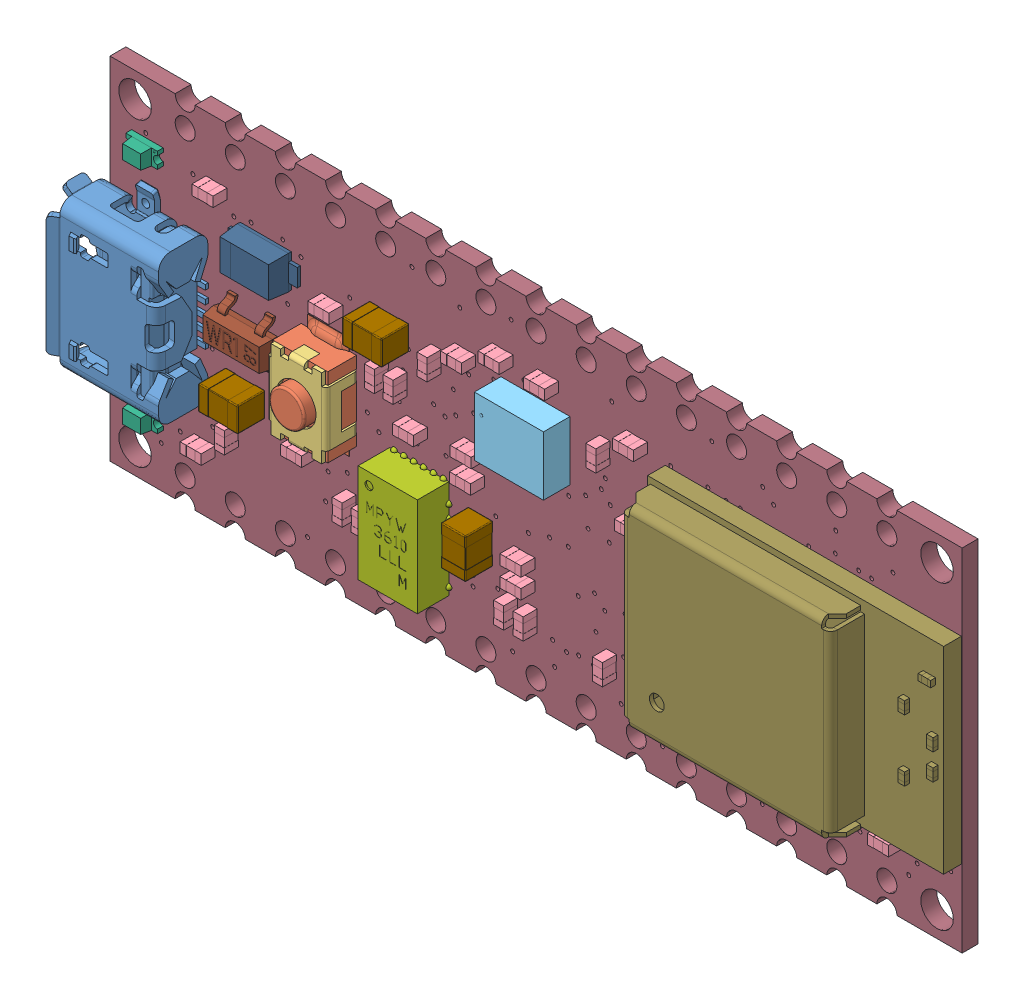
SolidWorks assembly Nano33BLE, configuration Default. Lengths in mm.
Overall size (43.8 17.78 3.58).
49 component instances, 13 part files, 0 mates.
Components (placement in the parent):
- Nano33BLE.step-1: Nano33BLE.step [Default] at origin size (43.8 17.78 3.58)
  - NANO33BLE_V2.0 v1.step-1: NANO33BLE_V2.0 v1.step [Default] at origin size (43.8 17.78 3.58)
    - 3DComponents.step-1: 3DComponents.step [Default] at origin size (43.76 12.41 2.95)
      - zx62-ab-5pa_31_ v1.step-1: zx62-ab-5pa_31_ v1.step [Default] x (-1 0 0) z (0 1 0) size (5.6 2.95 8.8)
        - 6850961.step-1: 6850961.step [Default] at origin size (5.6 2.95 8.8)
          - ZX62-AB-5PA (1).step-1: ZX62-AB-5PA (1).step [Default] at (-4.98 1.125 5.465) size (5.6 2.95 8.8)
      - IoT_Reser Button v1.step-1: IoT_Reser Button v1.step [Default] x (0 -1 0) z (-1 0 0) size (5.2 2.15 3)
        - User Library-arduino_nano_reset core.step-1: User Library-arduino_nano_reset core.step [Default] at (-8.89 0.805 -11.09) size (5.2 2.15 2.8)
        - User Library-arduino_nano_reset shell.step-1: User Library-arduino_nano_reset shell.step [Default] at (-8.89 2.455 -11.09) x (0 0 1) z (-1 0 0) size (3 1.65 4)
      - RC0402FR-071KL.step-1: RC0402FR-071KL.step [Default] at origin size (35.89 12.12 0.71)
        - RC0402FR-071KL RC0402N_YAG v1.step-1: RC0402FR-071KL RC0402N_YAG v1.step [Default] at (4.8 3.0875 0.805) size (1.07 0.51 0.71)
        - RC0402FR-071KL RC0402N_YAG v1.step-2: RC0402FR-071KL RC0402N_YAG v1.step [Default] at (6.25 4.4075 0.805) x (0 -1 0) z (0 0 1) size (1.07 0.51 0.71)
        - RC0402FR-071KL RC0402N_YAG v1.step-3: RC0402FR-071KL RC0402N_YAG v1.step [Default] at (9.8875 5.5375 0.805) size (1.07 0.51 0.71)
        - RC0402FR-071KL RC0402N_YAG v1.step-4: RC0402FR-071KL RC0402N_YAG v1.step [Default] at (11.27 12.5 0.805) size (1.07 0.51 0.71)
        - RC0402FR-071KL RC0402N_YAG v1.step-5: RC0402FR-071KL RC0402N_YAG v1.step [Default] at (5.4 14.7 0.805) size (1.07 0.51 0.71)
        - RC0402FR-071KL RC0402N_YAG v1.step-6: RC0402FR-071KL RC0402N_YAG v1.step [Default] at (12.225 4.225 0.805) x (0 1 0) z (0 0 1) size (1.07 0.51 0.71)
        - RC0402FR-071KL RC0402N_YAG v1.step-7: RC0402FR-071KL RC0402N_YAG v1.step [Default] at (13.1875 4.2375 0.805) x (0 1 0) z (0 0 1) size (1.07 0.51 0.71)
        - RC0402FR-071KL RC0402N_YAG v1.step-8: RC0402FR-071KL RC0402N_YAG v1.step [Default] at (13.85 10.9 0.805) x (0 -1 0) z (0 0 1) size (1.07 0.51 0.71)
        - RC0402FR-071KL RC0402N_YAG v1.step-9: RC0402FR-071KL RC0402N_YAG v1.step [Default] at (14.8 10.9 0.805) x (0 -1 0) z (0 0 1) size (1.07 0.51 0.71)
        - RC0402FR-071KL RC0402N_YAG v1.step-10: RC0402FR-071KL RC0402N_YAG v1.step [Default] at (15.55 9.275 0.805) size (1.07 0.51 0.71)
        - RC0402FR-071KL RC0402N_YAG v1.step-11: RC0402FR-071KL RC0402N_YAG v1.step [Default] at (16.525 12.75 0.805) x (0 -1 0) z (0 0 1) size (1.07 0.51 0.71)
        - RC0402FR-071KL RC0402N_YAG v1.step-12: RC0402FR-071KL RC0402N_YAG v1.step [Default] at (18 13.675 0.805) size (1.07 0.51 0.71)
        - RC0402FR-071KL RC0402N_YAG v1.step-13: RC0402FR-071KL RC0402N_YAG v1.step [Default] at (18.475 9.775 0.805) size (1.07 0.51 0.71)
        - RC0402FR-071KL RC0402N_YAG v1.step-14: RC0402FR-071KL RC0402N_YAG v1.step [Default] at (18.45 8.6 0.805) size (1.07 0.51 0.71)
        - RC0402FR-071KL RC0402N_YAG v1.step-15: RC0402FR-071KL RC0402N_YAG v1.step [Default] at (21 6.275 0.805) size (1.07 0.51 0.71)
        - RC0402FR-071KL RC0402N_YAG v1.step-16: RC0402FR-071KL RC0402N_YAG v1.step [Default] at (21 5.275 0.805) size (1.07 0.51 0.71)
        - RC0402FR-071KL RC0402N_YAG v1.step-17: RC0402FR-071KL RC0402N_YAG v1.step [Default] at (20.405 3.8 0.805) x (0 -1 0) z (0 0 1) size (1.07 0.51 0.71)
        - RC0402FR-071KL RC0402N_YAG v1.step-18: RC0402FR-071KL RC0402N_YAG v1.step [Default] at (21.395 3.8126 0.805) x (0 -1 0) z (0 0 1) size (1.07 0.51 0.71)
        - RC0402FR-071KL RC0402N_YAG v1.step-19: RC0402FR-071KL RC0402N_YAG v1.step [Default] at (25.075 13.025 0.805) x (0 -1 0) z (0 0 1) size (1.07 0.51 0.71)
        - RC0402FR-071KL RC0402N_YAG v1.step-20: RC0402FR-071KL RC0402N_YAG v1.step [Default] at (26.7 14.2 0.805) size (1.07 0.51 0.71)
        - RC0402FR-071KL RC0402N_YAG v1.step-21: RC0402FR-071KL RC0402N_YAG v1.step [Default] at (39.625 3.32 0.805) size (1.07 0.51 0.71)
        - RC0402FR-071KL RC0402N_YAG v1.step-22: RC0402FR-071KL RC0402N_YAG v1.step [Default] at (37.675 3.32 0.805) size (1.07 0.51 0.71)
        - RC0402FR-071KL RC0402N_YAG v1.step-23: RC0402FR-071KL RC0402N_YAG v1.step [Default] at (35.7 3.3125 0.805) size (1.07 0.51 0.71)
        - RC0402FR-071KL RC0402N_YAG v1.step-24: RC0402FR-071KL RC0402N_YAG v1.step [Default] at (25.4125 3.8125 0.805) x (0 -1 0) z (0 0 1) size (1.07 0.51 0.71)
        - RC0402FR-071KL RC0402N_YAG v1.step-25: RC0402FR-071KL RC0402N_YAG v1.step [Default] at (26.8 10.7 0.805) size (1.07 0.51 0.71)
        - RC0402FR-071KL RC0402N_YAG v1.step-26: RC0402FR-071KL RC0402N_YAG v1.step [Default] at (19.9 14.625 0.805) size (1.07 0.51 0.71)
        - RC0402FR-071KL RC0402N_YAG v1.step-27: RC0402FR-071KL RC0402N_YAG v1.step [Default] at (22.2 14.625 0.805) size (1.07 0.51 0.71)
      - LSM9DS1TR_LGA-24_3X3P5X1_STM v1.step-1: LSM9DS1TR_LGA-24_3X3P5X1_STM v1.step [Default] at (21.5608 12.1142 0.754) size (3.5 3 1.4)
      - IoT_HSMG-C190 LED v1.step-1: IoT_HSMG-C190 LED v1.step [Default] at (1.9 3.1 0.805) x (1 0 0) z (0 -1 0) size (1.6 0.8 0.8)
      - IoT_MPM3610 Step-Down Module v1.step-1: IoT_MPM3610 Step-Down Module v1.step [Default] at (15.675 5.1865 1.605) x (-1 0 0) z (0 1 0) size (3.3 1.65 5.15)
      - IoT_HSMG-C190 LED v1.step-2: IoT_HSMG-C190 LED v1.step [Default] at (1.9 14.7 0.805) x (1 0 0) z (0 -1 0) size (1.6 0.8 0.8)
      - BLM18EG101TN1D v1.step-1: BLM18EG101TN1D v1.step [Default] at (33.0875 2.8875 1.2047) size (1.6 0.65 0.8)
      - C0805C472KDRACTU v1.step-1: C0805C472KDRACTU v1.step [Default] at (14.1625 13 0.8053) x (1 0 0) z (0 -1 0) size (2 1.4 1.25)
      - C0805C472KDRACTU v1.step-2: C0805C472KDRACTU v1.step [Default] at (18.7875 6.0875 0.8053) x (0 -1 0) z (-1 0 0) size (2 1.4 1.25)
      - PMEG6020AELRX v1.step-1: PMEG6020AELRX v1.step [Default] at (7.9 12.95 0.805) x (1 0 0) z (0 -1 0) size (3.5 1.1 1.7)
      - C0805C472KDRACTU v1.step-3: C0805C472KDRACTU v1.step [Default] at (6.8675 6.425 0.8053) x (1 0 0) z (0 -1 0) size (2 1.4 1.25)
      - IoT_PRTR5V0U2X Protection Diode v1.step-1: IoT_PRTR5V0U2X Protection Diode v1.step [Default] at (7.23 9.3 1.455) x (1 0 0) z (0 -1 0) size (3 1.1 2.5)
      - NINA-B306-00B-00--3DModel-STEP-56544 v1.step-1: NINA-B306-00B-00--3DModel-STEP-56544 v1.step [Default] at (35.642 8.89 0.805) x (0 1 0) z (1 0 0) size (10 2.63 15)
    - Board (1).step-1: Board (1).step [Default] at origin size (43.18 17.78 0.81)
